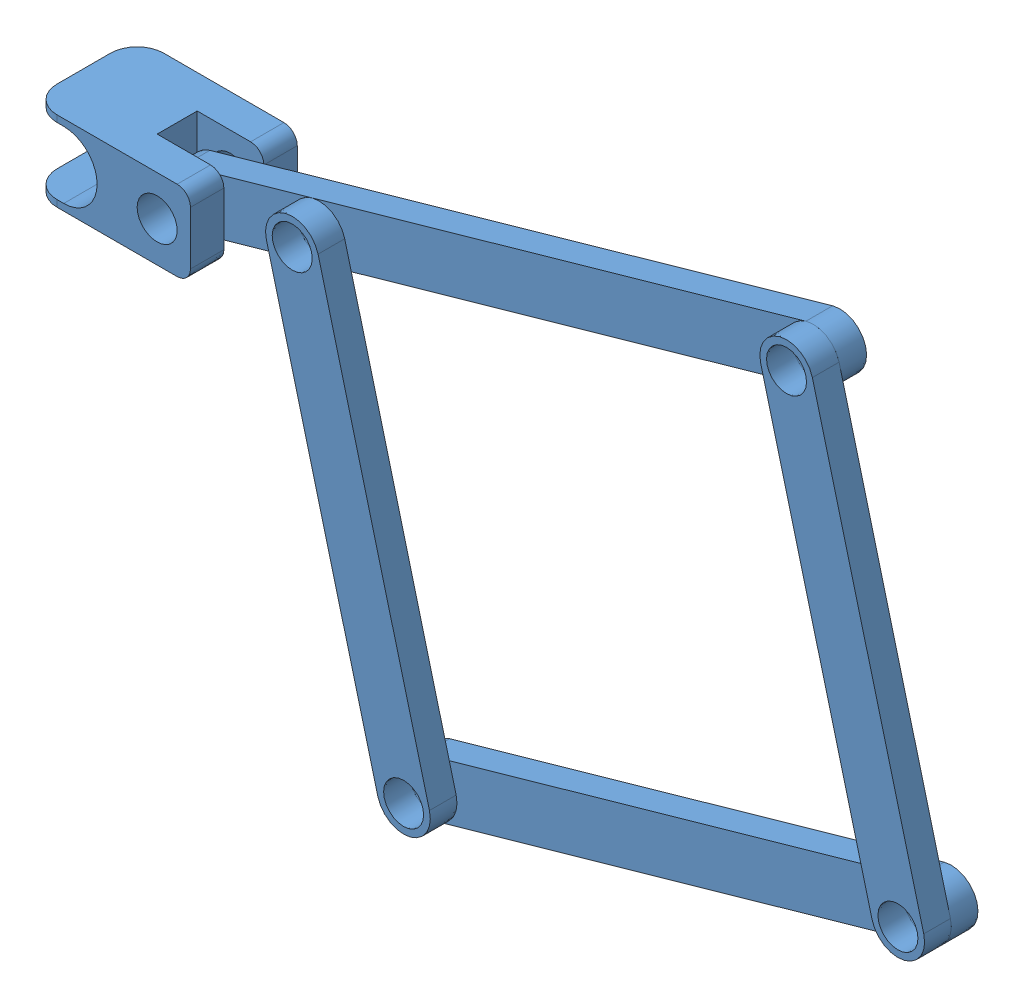
SolidWorks assembly 連動, configuration 預設. Lengths in mm.
Overall size (669.75 473.78 80).
5 component instances, 1 part files, 7 mates.
Components (placement in the parent):
- 夾-1: 夾 [夾頭端] at (-711.538 -7.0168 372.2931) x (0 0 -1) z (1 0 0) size (80 60 120)
- 夾-2: 夾 [上] at (-503.2512 59.1916 377.2931) x (0.962007 0.273024 0) z (0 0 1) size (525 40 20)
- 夾-3: 夾 [右] at (-186.49 -193.868 397.2931) x (0.967479 0.252953 0) z (0 0 1) size (40 370 20)
- 夾-4: 夾 [右] at (-556.8628 -298.9823 397.2931) x (0.967479 0.252953 0) z (0 0 1) size (40 370 20)
- 夾-5: 夾 [下] at (-371.6764 -246.4251 377.2931) x (0.962007 0.273024 0) z (0 0 1) size (425 40 20)
Mates (geometry in assembly coordinates):
- 重合/共線/共點1: coincident anti-aligned: cylinder of 夾-2 through (-269.9645 125.4 387.2931) axis (0 0 -1) radius 15; circle of 夾-3
- 重合/共線/共點2: coincident anti-aligned: plane of 夾-2 through (-269.9645 125.4 387.2931) normal (0 0 1); plane of 夾-3 through (-186.49 -193.868 387.2931) normal (0 0 -1)
- 重合/共線/共點3: coincident aligned: circle of 夾-1; circle of 夾-2
- 重合/共線/共點4: coincident aligned: circle of 夾-2; circle of 夾-4
- 同軸心1: concentric aligned: circle of 夾-4; circle of 夾-5
- 同軸心2: concentric aligned: circle of 夾-3; circle of 夾-5
- 重合/共線/共點8: coincident anti-aligned: plane of 夾-4 through (-556.8628 -298.9823 387.2931) normal (0 0 -1); plane of 夾-5 through (-186.49 -193.868 387.2931) normal (0 0 1)
